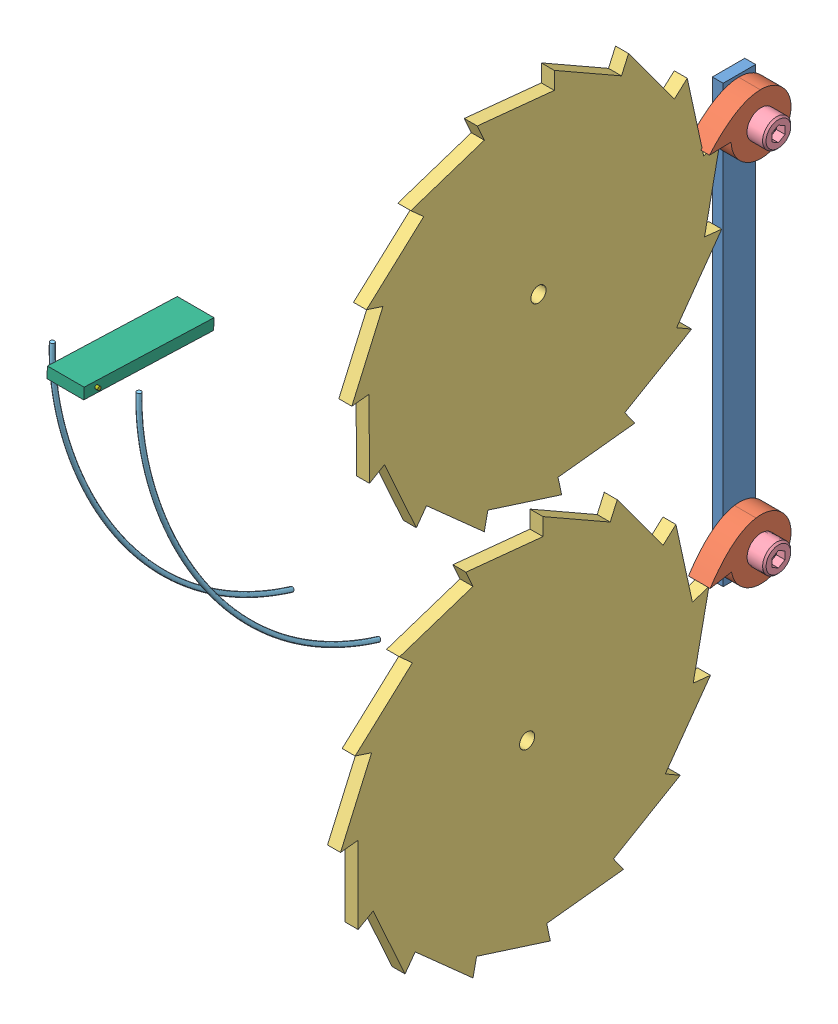
SolidWorks assembly LOck mechanism  - refernce assembly, configuration Default. Lengths in mm.
Overall size (42 347.08 358).
10 component instances, 7 part files, 12 mates.
Components (placement in the parent):
- lock meachanism - side board-1: lock meachanism - side board [Default] at (16.3378 53.7928 47.5798) size (5 201.25 15)
- Lock mechanism - rachet-1: Lock mechanism - rachet [Default] at (21.3378 79.7388 49.6408) x (1 0 0) z (0 -0.025077 0.999686) size (10 27.66 37.66)
- Lock mechanism - rachet-2: Lock mechanism - rachet [Default] at (21.3378 -85.3394 49.0529) x (1 0 0) z (0 -0.16657 0.98603) size (10 27.66 37.66)
- lock meachanism - catch-1: lock meachanism - catch [Default] at (21.3378 57.2738 146.4358) x (1 0 0) z (0 -0.000036 1) size (6 171.32 170.74)
- lock meachanism - catch-2: lock meachanism - catch [Default] at (21.3378 -118.4774 151.6545) x (1 0 0) z (0 -0.000036 1) size (6 171.32 170.74)
- socket head cap screw_am-1: socket head cap screw_am [B18.3.1M - 8 x 1.25 x 20 Hex SHCS -- 20NHX] at (39.3378 86.3278 83.9226) x (-1 0 0) z (0 0 -1) size (24 13 13)
- socket head cap screw_am-3: socket head cap screw_am [B18.3.1M - 8 x 1.25 x 16 Hex SHCS -- 16NHX] at (39.3378 -83.6778 83.9226) x (-1 0 0) z (0 0 -1) size (24 13 13)
- Rails-1: Rails [Default] at (6.3378 70.2683 319.6546) x (1 0 0) z (0 0.271009 0.962577) size (42 119.71 156.04)
- Retainer mechanism-2: Retainer mechanism [Default] at (-290.0894 133.9465 349.8349) x (0 -0.0366 -0.99933) z (1 0 0) size (60 5 16.96)
- pin-1: pin [Default] at (16.1532 137.0698 389.1446) x (1 0 0) z (0 -0.03601 0.999351) size (20 1.6 1.6)
Mates (geometry in assembly coordinates):
- Coincident1: coincident aligned: plane of lock meachanism - side board-1; plane of lock meachanism - side board-1 through (21.3378 53.7928 47.5798) normal (1 0 0)
- Coincident2: coincident: circle of lock meachanism - side board-1; circle of Lock mechanism - rachet-2
- Coincident6: coincident: plane of lock meachanism - side board-1 through (21.3378 53.7928 47.5798) normal (1 0 0); plane of lock meachanism - catch-1 through (21.3378 57.2738 146.4358) normal (-1 0 0)
- Coincident4: coincident: circle of Lock mechanism - rachet-1; circle of lock meachanism - side board-1
- Coincident8: coincident: plane of lock meachanism - side board-1 through (21.3378 53.7928 47.5798) normal (1 0 0); plane of lock meachanism - catch-2 through (21.3378 -118.4774 151.6545) normal (-1 0 0)
- Concentric11: concentric aligned: cylinder of Lock mechanism - rachet-1 through (31.3378 86.3278 83.9226) axis (1 0 0) radius 3.5; cylinder of socket head cap screw_am-1 through (71.0878 86.3278 83.9226) axis (1 0 0) radius 4
- Coincident91: coincident anti-aligned: plane of Lock mechanism - rachet-1 through (31.3378 86.3278 83.9226) normal (1 0 0); plane of socket head cap screw_am-1 through (31.3378 92.8278 83.9226) normal (-1 0 0)
- Concentric61: concentric aligned: cylinder of Lock mechanism - rachet-2 through (31.3378 -83.6778 83.9226) axis (1 0 0) radius 3.5; cylinder of socket head cap screw_am-3 through (71.0878 -83.6778 83.9226) axis (1 0 0) radius 4
- Coincident141: coincident anti-aligned: plane of Lock mechanism - rachet-2 through (31.3378 -83.6778 83.9226) normal (1 0 0); plane of socket head cap screw_am-3 through (31.3378 -77.1778 83.9226) normal (-1 0 0)
- Universal Joint1: universal joint: cylinder of Retainer mechanism-2 through (34.8164 138.0702 394.1204) axis (1 0 0) radius 0.8; cylinder of pin-1 through (36.1532 138.0702 394.1204) axis (-1 0 0) radius 0.8; unknown of ?
- Parallel8: parallel: line of Rails-1 through (45.3378 138.0702 394.1204) axis (-1 0 0); line of pin-1 through (36.1532 138.0702 394.1204) axis (-1 0 0)
- Coincident22: coincident: line of Rails-1 through (45.3378 138.0702 394.1204) axis (-1 0 0); line of pin-1 through (36.1532 138.0702 394.1204) axis (-1 0 0)
